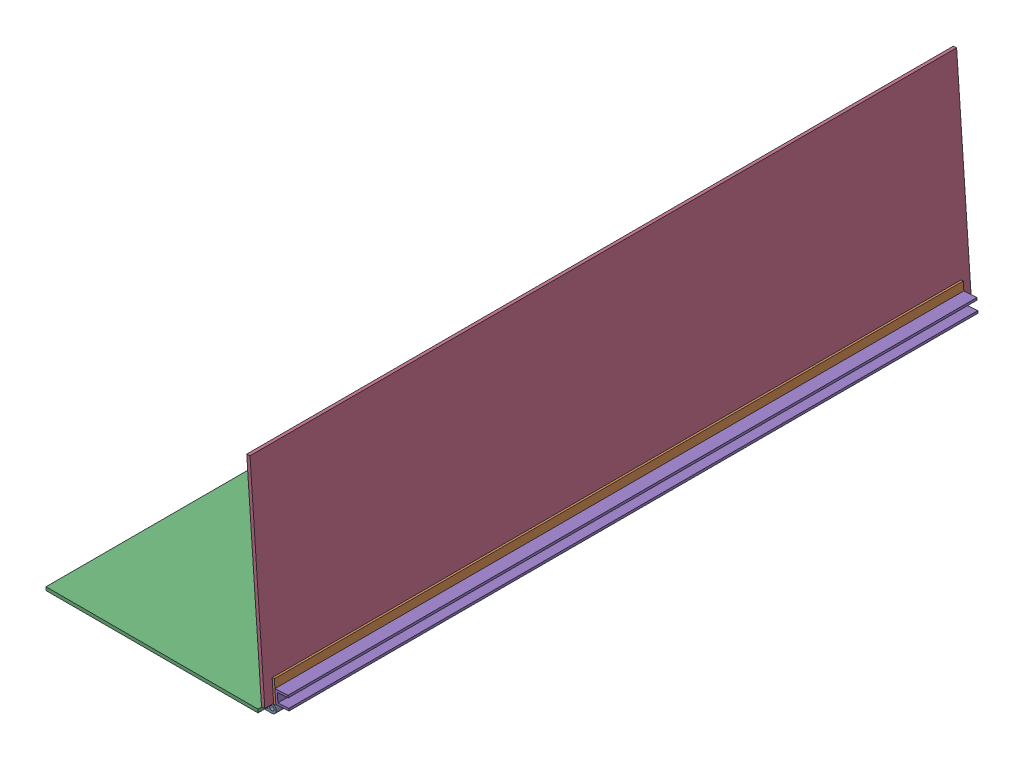
SolidWorks assembly FE-00014_ASSY_, configuration Default. Lengths in mm.
Overall size (336.78 321.43 1016).
8 component instances, 5 part files, 0 mates.
Components (placement in the parent):
- FE-00014-02ASSY_-1: FE-00014-02ASSY_ [Default] at origin size (44.88 45.23 990.6)
  - FE-00014-02_-1: FE-00014-02_ [Default] at origin size (44.45 12.7 990.6)
  - FE-00014-02_-2: FE-00014-02_ [Default] at (3.381 3.6257 990.6) x (0.069756 -0.997564 0) z (0 0 -1) size (44.45 12.7 990.6)
- FE-00014-01_-1: FE-00014-01_ [Default] at (-32.5438 3.175 14.2875) x (0 0 1) z (0 1 0) size (1016 304.8 4.76)
- FE-00014-01_-2: FE-00014-01_ [Default] at (-6.8073 35.5365 14.2875) x (0 0 1) z (0.997564 0.069756 0) size (1016 304.8 4.76)
- FE-00014-03_-1: FE-00014-03_ [Default] at (20.2245 37.4267 0) x (-0.069756 0.997564 0) z (0 0 1) size (19.05 19.05 990.6)
- FE-00014-04_-1: FE-00014-04_ [Default] at (-32.5438 9.9898 19.05) x (-1 0 0) z (0 0 -1) size (76.2 76.2 25.4)
- FE-00014-05_-1: FE-00014-05_ [Default] at (-76.3233 15.5704 20.4107) x (0 0 1) z (0.707107 0.707107 0) size (25.4 25.4 82.55)
